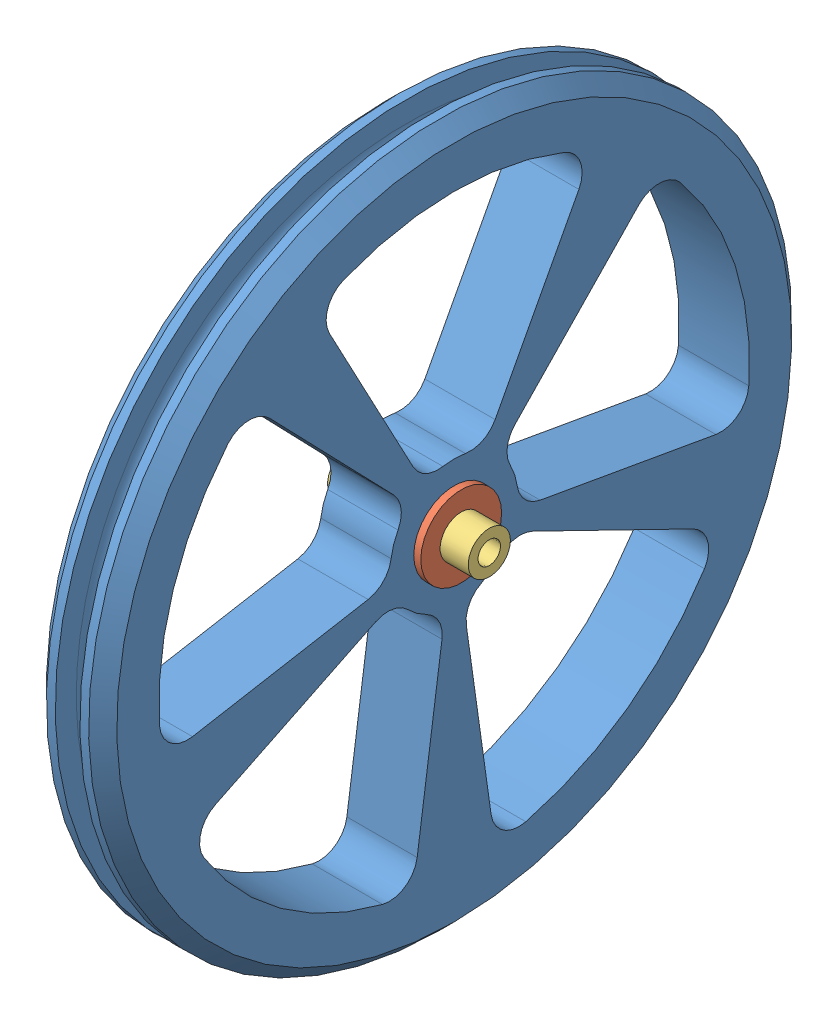
SolidWorks assembly Assemblage roue porteuse, configuration Default. Lengths in mm.
Overall size (20 100 100).
5 component instances, 3 part files, 4 mates.
Components (placement in the parent):
- Roue porteuse-1: Roue porteuse [Défaut] at origin size (10 100 100)
- Roulement F623ZZ-1: Roulement F623ZZ [Default] at (-6 0 0) size (4 11.5 11.5)
- Entretoise rouge 6x3.2x4-1: Entretoise rouge 6x3.2x4 [Default] at (-6 0 0) x (0 0.593547 0.804799) z (-1 0 0) size (6 6 4)
- Roulement F623ZZ-2: Roulement F623ZZ [Default] at (6 0 0) x (-1 0 0) z (0 0 -1) size (4 11.5 11.5)
- Entretoise rouge 6x3.2x4-2: Entretoise rouge 6x3.2x4 [Default] at (10 0 0) x (0 0.593547 0.804799) z (-1 0 0) size (6 6 4)
Mates (geometry in assembly coordinates):
- Coaxiale1: concentric aligned: cylinder of Roue porteuse-1 through (0 0 0) axis (-1 0 0) radius 5.05; cylinder of Roulement F623ZZ-1 through (-6 0 0) axis (-1 0 0) radius 5
- Coïncidente1: coincident anti-aligned: plane of Roue porteuse-1 through (-5 0 0) normal (-1 0 0); plane of Roulement F623ZZ-1 through (-5 0 -5.75) normal (1 0 0)
- Coaxiale2: concentric anti-aligned: cylinder of Roulement F623ZZ-1 through (-6 0 0) axis (-1 0 0) radius 5.75; cylinder of Entretoise rouge 6x3.2x4-1 through (-10 0 0) axis (1 0 0) radius 3
- Coïncidente2: coincident anti-aligned: plane of Roulement F623ZZ-1 through (-6 0 -1.5) normal (-1 0 0); plane of Entretoise rouge 6x3.2x4-1 through (-6 0 0) normal (1 0 0)
